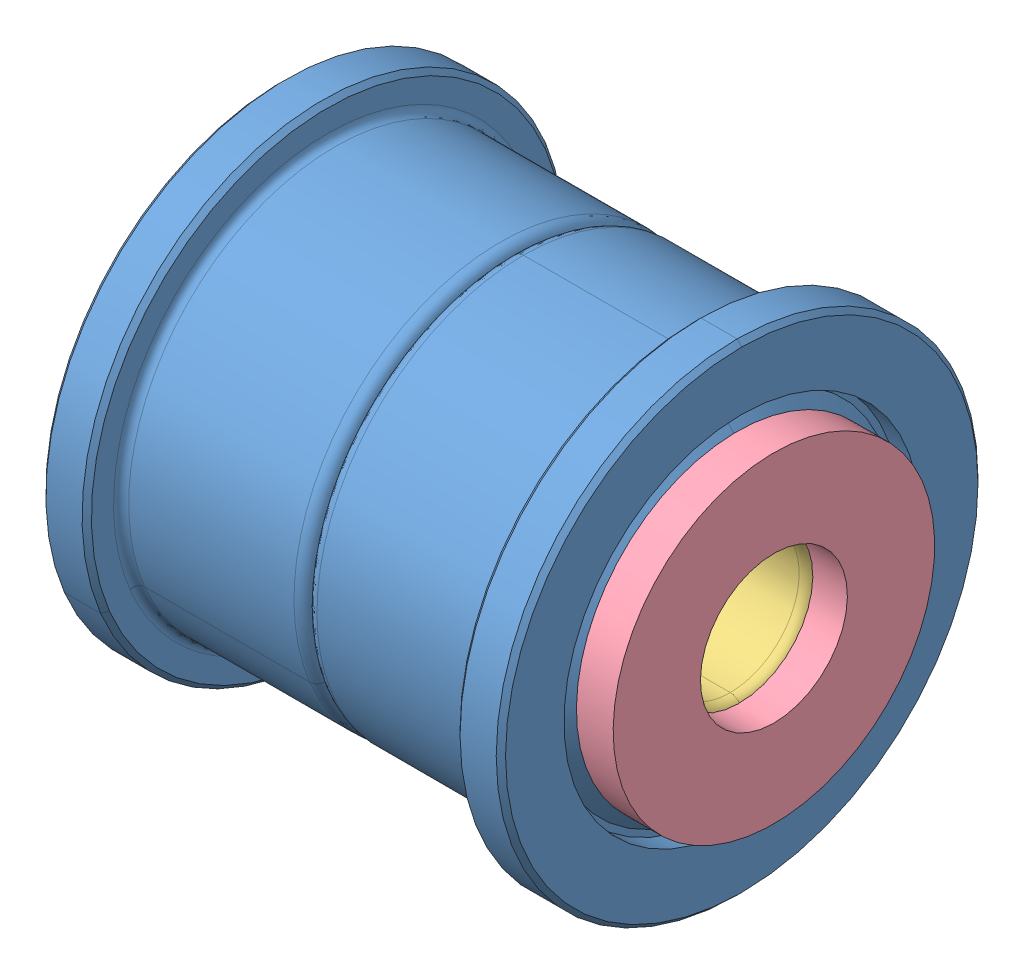
SolidWorks assembly Bearing assembly, configuration Default. Lengths in mm.
Overall size (22.35 13.72 13.72).
11 component instances, 6 part files, 7 mates.
Components (placement in the parent):
- F603HZZ-1: F603HZZ [Default] at origin size (5 10.49 10.49)
  - F603HZZ_SOLID_1-1: F603HZZ_SOLID_1 [Default] at origin size (5 10.49 10.49)
  - F603HZZ_SOLID_2-1: F603HZZ_SOLID_2 [Default] at origin size (3.13 7.92 8.2)
  - F603HZZ_SOLID_3-1: F603HZZ_SOLID_3 [Default] at origin size (5 4.24 4.24)
- F603HZZ-2: F603HZZ [Default] at (-5.0038 0 0) x (-1 0 0) z (0 -0.922978 -0.384852) size (5 10.49 10.49)
  - F603HZZ_SOLID_1-1: F603HZZ_SOLID_1 [Default] at origin size (5 10.49 10.49)
  - F603HZZ_SOLID_2-1: F603HZZ_SOLID_2 [Default] at origin size (3.13 7.92 8.2)
  - F603HZZ_SOLID_3-1: F603HZZ_SOLID_3 [Default] at origin size (5 4.24 4.24)
- plain washer 10673 type snl_iso-1: plain washer 10673 type snl_iso [ISO 10673-3.2-S] at (2.4018 0 0) x (1 0 0) z (0 0.016518 0.999864) size (0.8 7 7)
- pan head cross recess screw_iso-1: pan head cross recess screw_iso [ISO 7045 - M3 x 20 - Z --- 20N] at (-9.9057 0 0) x (1 0 0) z (0 -0.190019 0.98178) size (22.35 5.6 5.6)
- hex thin nut chamfered gradeab_iso-1: hex thin nut chamfered gradeab_iso [Hexagon Thin Nut ISO - 4035 - M3 - N] at (9.0018 0 0) x (0 0.857652 -0.514231) z (1 0 0) size (5.5 6.35 1.8)
Mates (geometry in assembly coordinates):
- Concentric401055: concentric: cylinder of F603HZZ-1/F603HZZ_SOLID_3-1 through (-2.7521 0 0) axis (1 0 0) radius 1.4986; cylinder of F603HZZ-2/F603HZZ_SOLID_3-1 through (-2.2517 0 0) axis (-1 0 0) radius 1.4986
- Coincident7871306: coincident: plane of F603HZZ-1/F603HZZ_SOLID_1-1 through (-2.5019 0 0) normal (-1 0 0); plane of F603HZZ-2/F603HZZ_SOLID_1-1 through (-2.5019 0 0) normal (1 0 0)
- Coincident7871309: coincident: plane of F603HZZ-1/F603HZZ_SOLID_1-1 through (2.4018 0 0) normal (1 0 0); plane of plain washer 10673 type snl_iso-1 through (2.4018 0 0) normal (-1 0 0)
- Concentric401065: concentric: cylinder of pan head cross recess screw_iso-1 through (-35.3057 0 0) axis (-1 0 0) radius 1.5; cylinder of plain washer 10673 type snl_iso-1 through (3.2018 0 0) axis (-1 0 0) radius 1.6
- Concentric401068: concentric: cylinder of F603HZZ-2/F603HZZ_SOLID_3-1 through (-2.2517 0 0) axis (-1 0 0) radius 1.4986; cylinder of pan head cross recess screw_iso-1 through (-35.3057 0 0) axis (-1 0 0) radius 2.8
- Coincident7871314: coincident: plane of F603HZZ-2/F603HZZ_SOLID_1-1 through (-7.5057 0 0) normal (-1 0 0); plane of pan head cross recess screw_iso-1 through (-7.5057 1.4727 0.285) normal (1 0 0)
- Concentric401212: concentric: cylinder of pan head cross recess screw_iso-1 through (-35.3057 0 0) axis (-1 0 0) radius 1.5; circle of hex thin nut chamfered gradeab_iso-1
